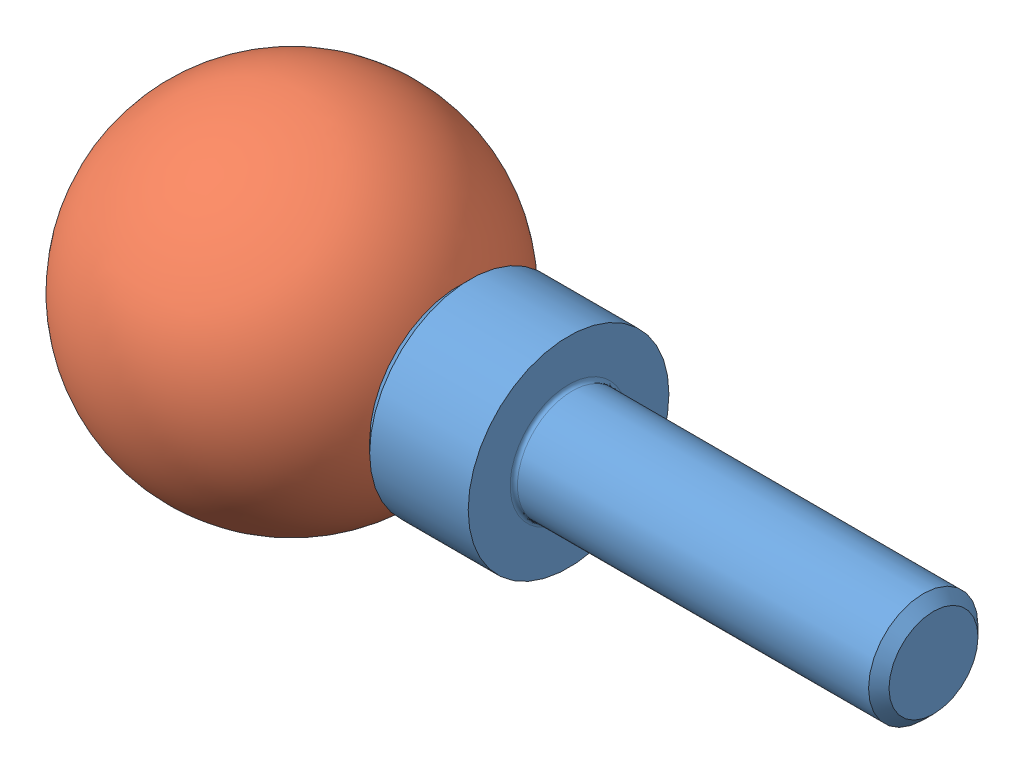
SolidWorks assembly Assem-ball on nut, configuration Default. Lengths in mm.
Overall size (22.35 12.89 12.89).
2 component instances, 2 part files, 2 mates.
Components (placement in the parent):
- socket head cap screw_am-1: socket head cap screw_am [B18.3.1M - 3 x 0.5 x 10 Hex SHCS -- 10NHX] at (-20.2329 3.4218 -0.8826) size (13 5.5 5.5)
- Part-ebay-3-8 sling shot ammo-1: Part-ebay-3-8 sling shot ammo [Default] at (-24.8202 3.4218 -0.8826) x (1 0 0) z (0 -0.472388 -0.881391) size (9.53 9.53 9.53)
Mates (geometry in assembly coordinates):
- Coincident1: coincident aligned: line of Part-ebay-3-8 sling shot ammo-1 through (-19.5814 3.4218 -0.8826) axis (-1 0 0)
- Coincident3: coincident: point of socket head cap screw_am-1; unknown of Part-ebay-3-8 sling shot ammo-1
